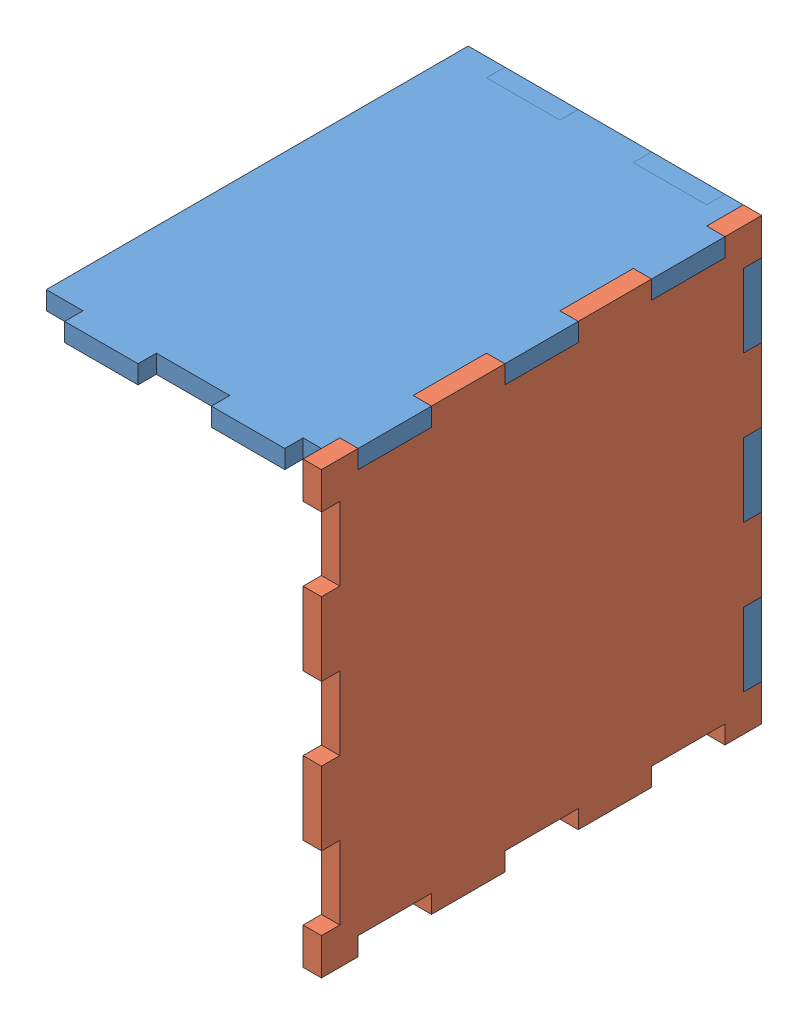
SolidWorks assembly 3x3x2, configuration Default. Lengths in mm.
Overall size (50.8 76.2 76.2).
3 component instances, 2 part files, 6 mates.
Components (placement in the parent):
- 3x2 side-1: 3x2 side [Default] at origin size (50.8 76.2 3.17)
- 3x3 bottom-1: 3x3 bottom [Default] at (47.625 0 76.2) x (0 0 -1) z (1 0 0) size (76.2 76.2 3.17)
- 3x2 side-2: 3x2 side [Default] at (0 76.2 0) x (1 0 0) z (0 -1 0) size (50.8 76.2 3.17)
Mates (geometry in assembly coordinates):
- Coincident1: coincident aligned: plane of ?; plane of ?
- Coincident2: coincident aligned: plane of ?; plane of ?
- Coincident3: coincident aligned: plane of ?; plane of ?
- Coincident4: coincident aligned: plane of ?; plane of ?
- Coincident5: coincident aligned: plane of ?; plane of ?
- Coincident6: coincident aligned: plane of ?; plane of ?
